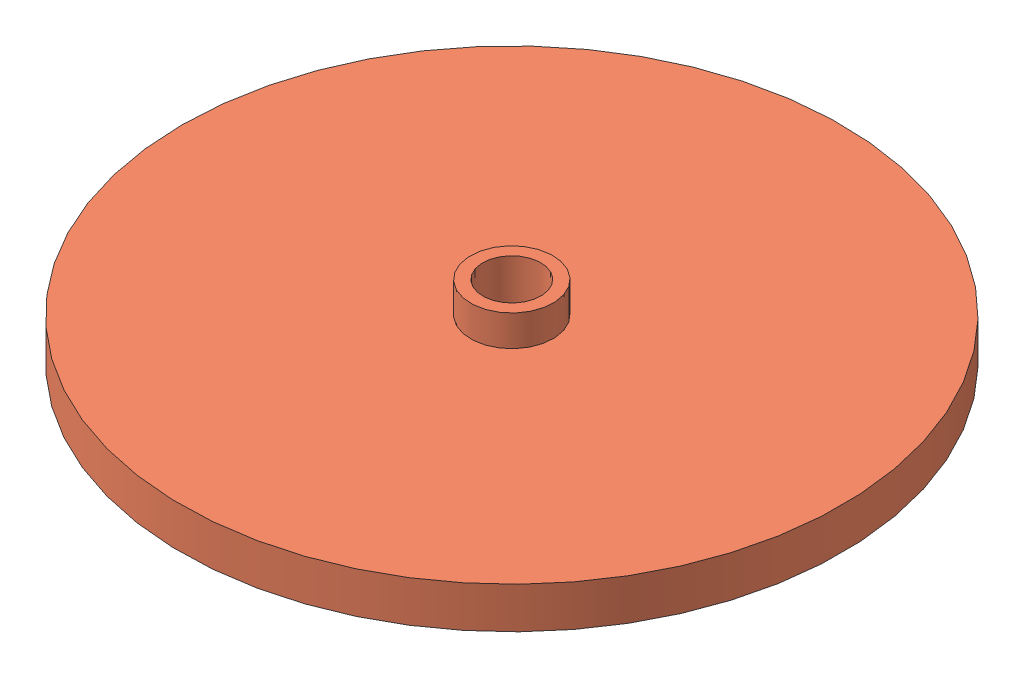
SolidWorks assembly impinging injector concept, configuration Default. Lengths in mm.
Overall size (240.65 43.56 240.65).
2 component instances, 2 part files, 3 mates.
Components (placement in the parent):
- injector plate-1: injector plate [Default] at origin size (101.6 21.34 101.6)
- impinging dome-1: impinging dome [Default] at (0 30.861 0) x (0.978615 0 0.205698) z (-0.205698 0 0.978615) size (203.2 22.23 203.2)
Mates (geometry in assembly coordinates):
- Coincident1: coordinate: point of injector plate-1
- Concentric1: concentric anti-aligned: cylinder of injector plate-1 through (0 18.161 0) axis (0 1 0) radius 50.8; cylinder of impinging dome-1 through (0 24.511 0) axis (0 -1 0) radius 101.6
- Coincident2: coincident anti-aligned: plane of injector plate-1 through (-50.8 18.161 0) normal (0 1 0); plane of impinging dome-1 through (-99.4273 18.161 -20.8989) normal (0 -1 0)
